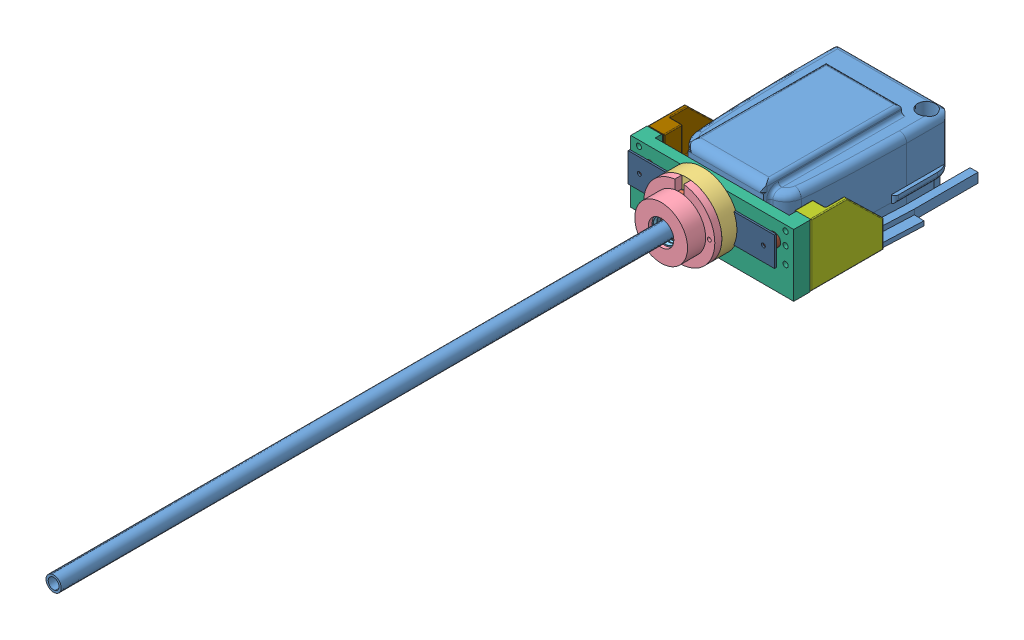
SolidWorks assembly Assem1, configuration Default. Lengths in mm.
Overall size (90 54.62 474).
14 component instances, 12 part files, 30 mates.
Components (placement in the parent):
- Shaft-1: Shaft [Default] at (-12.9165 9.0223 -130.1903) size (83.99 43.05 474)
- Z_dir_Ring_middle-1: Z_dir_Ring_middle [Default] at (-15.1953 8.9679 -119.3999) x (0.999716 0.023842 0) z (0 0 1) size (23.88 23.88 10.61)
- Z_dir_Ring_top-1: Z_dir_Ring_top [Default] at (-12.9165 9.0223 -118.5936) size (39.24 39.24 9.31)
- Z_dir_Ring2_bot-1: Z_dir_Ring2_bot [Default] at (-12.9165 9.0223 -103.6204) x (-1 0 0) z (0 0 -1) size (39.24 39.08 13.89)
- 6655K170_PLASTIC THRUST BALL BEARING-1: 6655K170_PLASTIC THRUST BALL BEARING [6655K17] at (-12.9165 9.0223 -116.9568) x (0.995192 -0.097945 0) z (-0.097945 -0.995192 0) size (23.81 6.32 23.81)
- 6655K170_PLASTIC THRUST BALL BEARING-2: 6655K170_PLASTIC THRUST BALL BEARING [6655K17] at (-12.9165 9.0223 -104.0822) x (0.999847 0.017471 0) z (-0.017471 0.999847 0) size (23.81 6.32 23.81)
- base2_1-1: base2_1 [Default] at (-57.9165 -25.9777 -127.1191) x (1 0 0) z (0 1 0) size (90 9.53 45)
- base_wing-1: base_wing [Default] at (32.0835 -15.3777 -136.6441) x (-1 0 0) z (0 0 -1) size (9 34.4 40)
- 90240A007_TAPPING INSERT-1: 90240A007_TAPPING INSERT [90240A007] at (26.0835 -1.7341 -171.6441) x (0.954713 0 -0.297528) z (0.297528 0 0.954713) size (4.47 6.33 5.05)
- base_wing - lef-1: base_wing - lef [Default] at (-39.9165 -15.3777 -136.6441) x (-1 0 0) z (0 0 -1) size (9 34.4 40)
- Part2^Assem1-1: Part2^Assem1 [Default] at origin (virtual)
- Z_dir_plate_3-1: Z_dir_plate_3 [Default] at (-12.0306 -5.2434 -122.1191) x (1 0 0) z (0 -1 0) size (80.82 1 16)
- Z_dir_conn_plate-1: Z_dir_conn_plate [Default] at (-47.1665 9.0223 -127.1191) size (7 7 5)
- Z_dir_conn_plate-2: Z_dir_conn_plate [Default] at (21.3335 9.0223 -127.1191) size (7 7 5)
Mates (geometry in assembly coordinates):
- Concentric2: concentric aligned: cylinder of Shaft-1 through (-12.9165 9.0223 236.6097) axis (0 0 -1) radius 4.2; cylinder of Z_dir_Ring_middle-1 through (-12.9165 9.0223 -138.5299) axis (0 0 -1) radius 4.2
- Concentric4: concentric aligned: cylinder of Z_dir_Ring_middle-1 through (-12.9165 9.0223 -138.5299) axis (0 0 -1) radius 6.35; cylinder of 6655K170_PLASTIC THRUST BALL BEARING-1 through (-12.9165 9.0223 -120.1191) axis (0 0 -1) radius 6.3881
- Coincident4: coincident anti-aligned: plane of Z_dir_Ring_middle-1 through (-15.1953 8.9679 -113.7945) normal (0 0 -1); plane of 6655K170_PLASTIC THRUST BALL BEARING-1 through (-14.0827 -2.8267 -113.7945) normal (0 0 1)
- Concentric5: concentric anti-aligned: cylinder of 6655K170_PLASTIC THRUST BALL BEARING-2 through (-12.9165 9.0223 -100.9199) axis (0 0 1) radius 6.3881; cylinder of Z_dir_Ring_middle-1 through (-12.9165 9.0223 -138.5299) axis (0 0 -1) radius 6.35
- Coincident5: coincident anti-aligned: plane of Z_dir_Ring_middle-1 through (-15.1953 8.9679 -107.2445) normal (0 0 1); plane of 6655K170_PLASTIC THRUST BALL BEARING-2 through (-13.1245 20.9267 -107.2445) normal (0 0 -1)
- Concentric6: concentric aligned: cylinder of Z_dir_Ring_top-1 through (-12.9165 9.0223 -144.0049) axis (0 0 -1) radius 11.938; cylinder of 6655K170_PLASTIC THRUST BALL BEARING-1 through (-12.9165 9.0223 -120.1191) axis (0 0 -1) radius 11.9062
- Concentric12: concentric anti-aligned: cylinder of Shaft-1 through (-12.9165 9.0223 236.6097) axis (0 0 -1) radius 4.2; cylinder of Z_dir_Ring2_bot-1 through (-12.9165 9.0223 -78.2091) axis (0 0 1) radius 7
- Concentric13: concentric anti-aligned: cylinder of Z_dir_Ring_top-1 through (3.6535 9.0223 -112.8091) axis (0 0 -1) radius 1.0922; cylinder of Z_dir_Ring2_bot-1 through (3.6535 9.0223 -112.8099) axis (0 0 1) radius 1.0922
- Coincident17: coincident anti-aligned: plane of Z_dir_Ring_top-1 through (-12.9165 9.0223 -120.1191) normal (0 0 1); plane of 6655K170_PLASTIC THRUST BALL BEARING-1 through (-14.0827 -2.8267 -120.1191) normal (0 0 -1)
- Coincident18: coincident anti-aligned: plane of Z_dir_Ring2_bot-1 through (-12.9165 9.0223 -100.9199) normal (0 0 -1); plane of 6655K170_PLASTIC THRUST BALL BEARING-2 through (-13.1245 20.9267 -100.9199) normal (0 0 1)
- Coincident21: coincident anti-aligned: plane of base2_1-1 through (-57.9165 19.0223 -136.6441) normal (0 0 -1); plane of base_wing-1 through (32.0835 -15.3777 -136.6441) normal (0 0 1)
- Concentric30: concentric anti-aligned: cylinder of base2_1-1 through (27.5835 0.0223 -126.6441) axis (0 0 -1) radius 1.4224; cylinder of base_wing-1 through (27.5835 0.0223 -146.6441) axis (0 0 1) radius 1.42
- Concentric31: concentric anti-aligned: cylinder of base2_1-1 through (27.5835 9.0223 -126.6441) axis (0 0 -1) radius 1.4224; cylinder of base_wing-1 through (27.5835 9.0223 -146.6441) axis (0 0 1) radius 1.42
- Parallel2: parallel aligned: plane of Shaft-1 through (21.1835 24.7723 -227.3903) normal (0 1 0); plane of base2_1-1 through (-57.9165 19.0223 -127.1191) normal (0 1 0)
- Coincident25: coincident anti-aligned: plane of Shaft-1 through (-12.9165 -15.8177 -130.6441) normal (0 0 1); plane of base2_1-1 through (-57.9165 -25.9777 -130.6441) normal (0 0 -1)
- Concentric36: concentric aligned: cylinder of Shaft-1 through (-12.9165 9.0223 236.6097) axis (0 0 -1) radius 4.2; cylinder of base2_1-1 through (-12.9165 9.0223 -126.6441) axis (0 0 -1) radius 7
- Concentric37: concentric aligned: cylinder of base_wing-1 through (26.0835 4.6223 -171.6441) axis (0 -1 0) radius 2.0193; circle of 90240A007_TAPPING INSERT-1
- Coincident26: coincident aligned: plane of base_wing-1 through (29.0835 -7.6777 -136.6441) normal (0 -1 0); plane of 90240A007_TAPPING INSERT-1 through (26.0835 -7.6777 -171.6441) normal (0 -1 0)
- Concentric38: concentric anti-aligned: cylinder of base2_1-1 through (-53.4165 9.0223 -126.6441) axis (0 0 -1) radius 1.4224; cylinder of base_wing - lef-1 through (-53.4165 9.0223 -146.6441) axis (0 0 1) radius 1.4224
- Concentric39: concentric anti-aligned: cylinder of base2_1-1 through (-53.4165 0.0223 -126.6441) axis (0 0 -1) radius 1.4224; cylinder of base_wing - lef-1 through (-53.4165 0.0223 -146.6441) axis (0 0 1) radius 1.4224
- Coincident27: coincident anti-aligned: plane of base2_1-1 through (-57.9165 19.0223 -136.6441) normal (0 0 -1); plane of base_wing - lef-1 through (-39.9165 -15.3777 -136.6441) normal (0 0 1)
- Parallel3: parallel aligned: plane of Z_dir_Ring_top-1 through (9.6454 1.0223 -121.1191) normal (0 1 0); plane of base2_1-1 through (-57.9165 19.0223 -127.1191) normal (0 1 0)
- Concentric40: concentric anti-aligned: cylinder of Shaft-1 through (-12.9165 9.0223 236.6097) axis (0 0 -1) radius 4.2; circle of Z_dir_plate_3-1
- Coincident28: coincident anti-aligned: plane of Z_dir_Ring_top-1 through (-12.9165 9.0223 -121.1191) normal (0 0 -1); plane of Z_dir_plate_3-1 through (-12.0306 -5.2434 -121.1191) normal (0 0 1)
- Concentric41: concentric aligned: cylinder of base2_1-1 through (21.3335 9.0223 -126.6441) axis (0 0 -1) radius 1.1303; cylinder of Z_dir_plate_3-1 through (21.3335 9.0223 -121.1191) axis (0 0 -1) radius 1.09
- Coincident29: coincident anti-aligned: plane of base2_1-1 through (-57.9165 19.0223 -127.1191) normal (0 0 1); plane of Z_dir_conn_plate-1 through (-47.1665 9.0223 -127.1191) normal (0 0 -1)
- Concentric42: concentric aligned: cylinder of Z_dir_plate_3-1 through (-47.1665 9.0223 -121.1191) axis (0 0 -1) radius 1.09; cylinder of Z_dir_conn_plate-1 through (-47.1665 9.0223 -122.1191) axis (0 0 -1) radius 1.25
- Coincident30: coincident anti-aligned: plane of Z_dir_plate_3-1 through (-12.0306 -5.2434 -122.1191) normal (0 0 -1); plane of Z_dir_conn_plate-1 through (-47.1665 9.0223 -122.1191) normal (0 0 1)
- Concentric43: concentric aligned: cylinder of Z_dir_plate_3-1 through (21.3335 9.0223 -121.1191) axis (0 0 -1) radius 1.09; cylinder of Z_dir_conn_plate-2 through (21.3335 9.0223 -122.1191) axis (0 0 -1) radius 1.25
- Coincident31: coincident anti-aligned: plane of Z_dir_plate_3-1 through (-12.0306 -5.2434 -122.1191) normal (0 0 -1); plane of Z_dir_conn_plate-2 through (21.3335 9.0223 -122.1191) normal (0 0 1)
